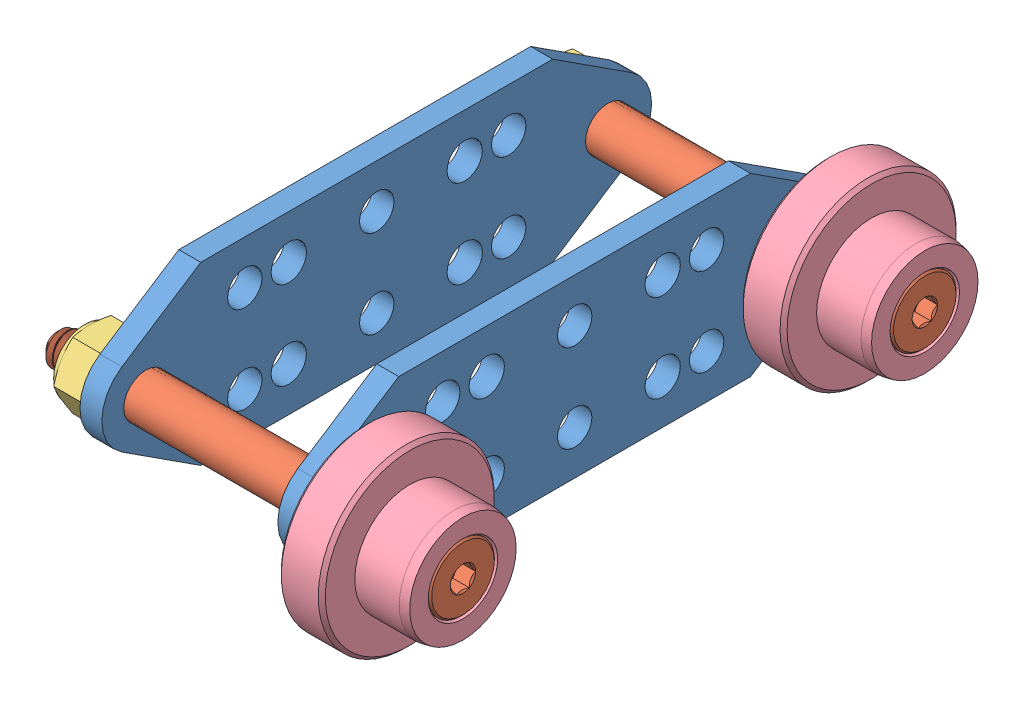
SolidWorks assembly CRP_E_001, configuration Default. Lengths in mm.
Overall size (58.92 25.4 92.08).
8 component instances, 4 part files, 0 mates.
Components (placement in the parent):
- CRP_ELE_V2_002-1: CRP_ELE_V2_002 [Default] x (0 0 -1) z (1 0 0) size (79.38 25.4 3.18)
- CRP_ELE_V2_002-2: CRP_ELE_V2_002 [Default] at (-28.575 0 0) x (0 0 -1) z (1 0 0) size (79.38 25.4 3.18)
- Shoulder_Screw_.25dia_1.75long_10-24_91259A102-1: Shoulder_Screw_.25dia_1.75long_10-24_91259A102 [Default] at (15.621 0 33.3375) x (0 -1 0) z (0 0 1) size (9.53 58.92 9.53)
- Shoulder_Screw_.25dia_1.75long_10-24_91259A102-2: Shoulder_Screw_.25dia_1.75long_10-24_91259A102 [Default] at (15.621 0 -33.3375) x (0 -1 0) z (0 0 1) size (9.53 58.92 9.53)
- Nut_Nylock_10-24_ZP_90631A011-1: Nut_Nylock_10-24_ZP_90631A011 [Default] at (-28.575 0 33.3375) x (0 1 0) z (0 0 1) size (9.53 6.11 11)
- Nut_Nylock_10-24_ZP_90631A011-2: Nut_Nylock_10-24_ZP_90631A011 [Default] at (-28.575 0 -33.3375) x (0 1 0) z (0 0 1) size (9.53 6.11 11)
- CRP_ELE_V2_001-1: CRP_ELE_V2_001 [Default] at (3.175 0 33.3375) size (17.21 25.4 25.4)
- CRP_ELE_V2_001-2: CRP_ELE_V2_001 [Default] at (3.175 0 -33.3375) size (17.21 25.4 25.4)
